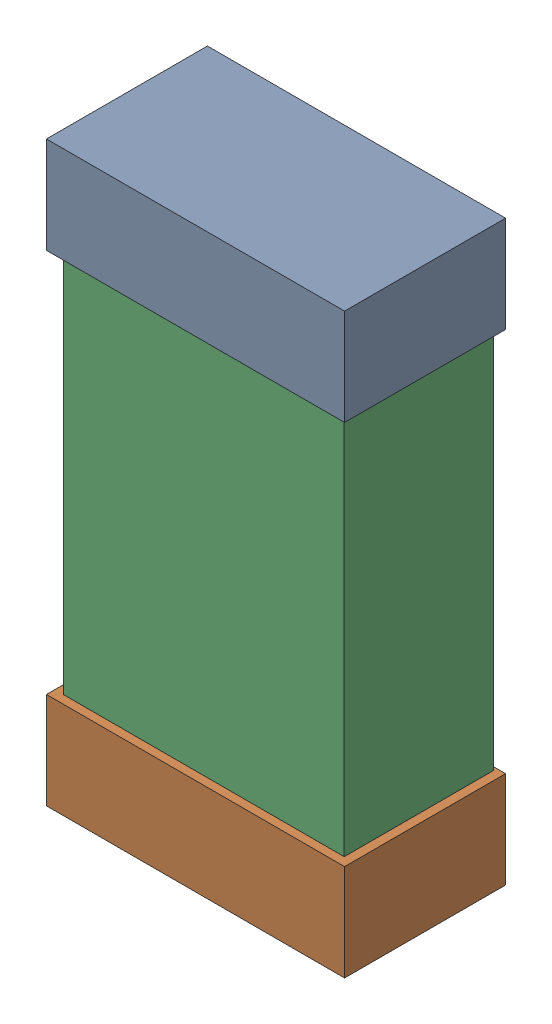
SolidWorks assembly R25, configuration Default. Lengths in mm.
Overall size (0.85 1.65 0.46).
6 component instances, 2 part files, 0 mates.
Components (placement in the parent):
- 432138512_110-1: 432138512_110 [Default] at (17.2851 20.139 -0.8715) size (0.85 0.28 0.46)
  - Extruded-1: Extruded [Default] at origin size (0.85 0.28 0.46)
- 432138512_111-1: 432138512_111 [Default] at (17.2851 18.7675 -0.8715) size (0.85 0.28 0.46)
  - Extruded-1: Extruded [Default] at origin size (0.85 0.28 0.46)
- 432124816_55-1: 432124816_55 [Default] at (17.2851 19.4533 -0.8615) size (0.8 1.5 0.42)
  - Extruded (1)-1: Extruded (1) [Default] at origin size (0.8 1.5 0.42)
